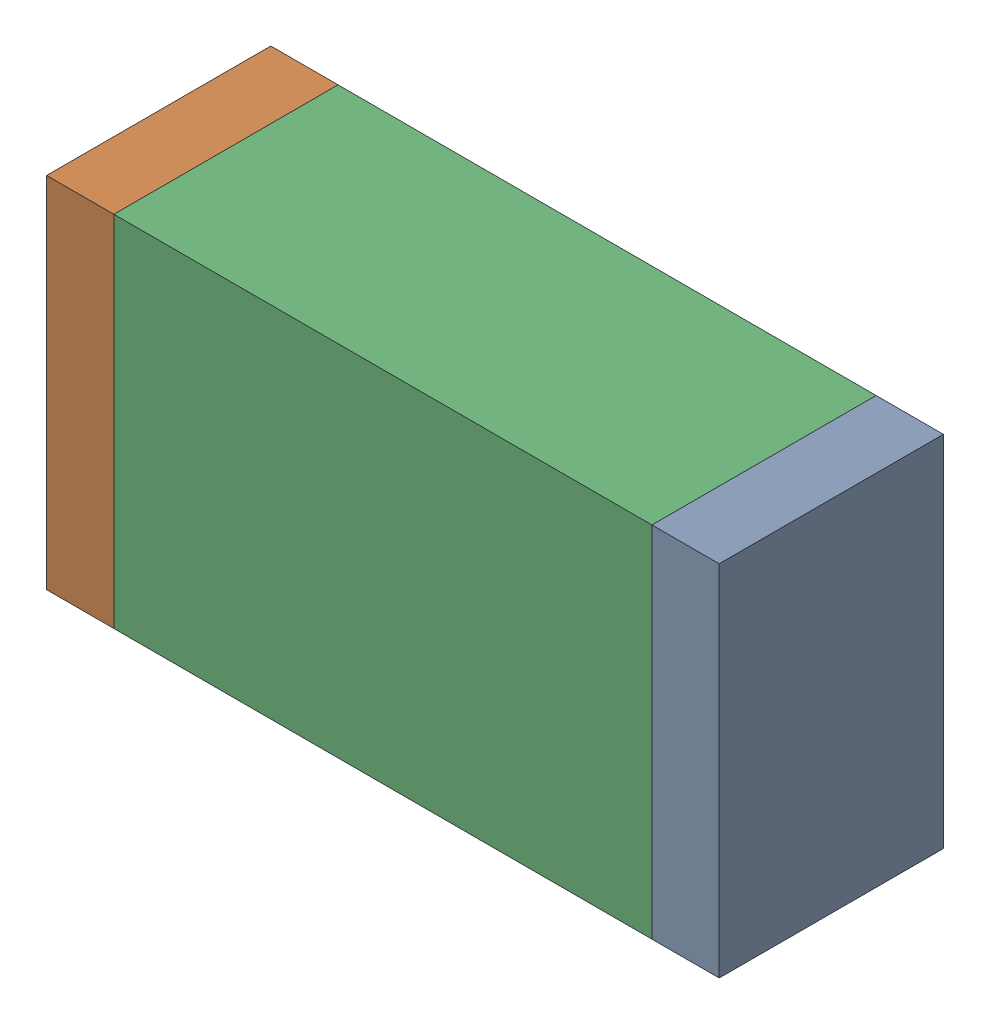
SolidWorks assembly R67, configuration Default. Lengths in mm.
Overall size (1.5 0.8 0.5).
6 component instances, 2 part files, 0 mates.
Components (placement in the parent):
- 836752496-1: 836752496 [Default] at (115.775 74.3 0) size (0.15 0.8 0.5)
  - Extruded_2-1: Extruded_2 [Default] at origin size (0.15 0.8 0.5)
- 836752496-2: 836752496 [Default] at (114.425 74.3 0) size (0.15 0.8 0.5)
  - Extruded_2-1: Extruded_2 [Default] at origin size (0.15 0.8 0.5)
- 836752368-1: 836752368 [Default] at (115.1 74.3 0) size (1.2 0.8 0.5)
  - Extruded-1: Extruded [Default] at origin size (1.2 0.8 0.5)
